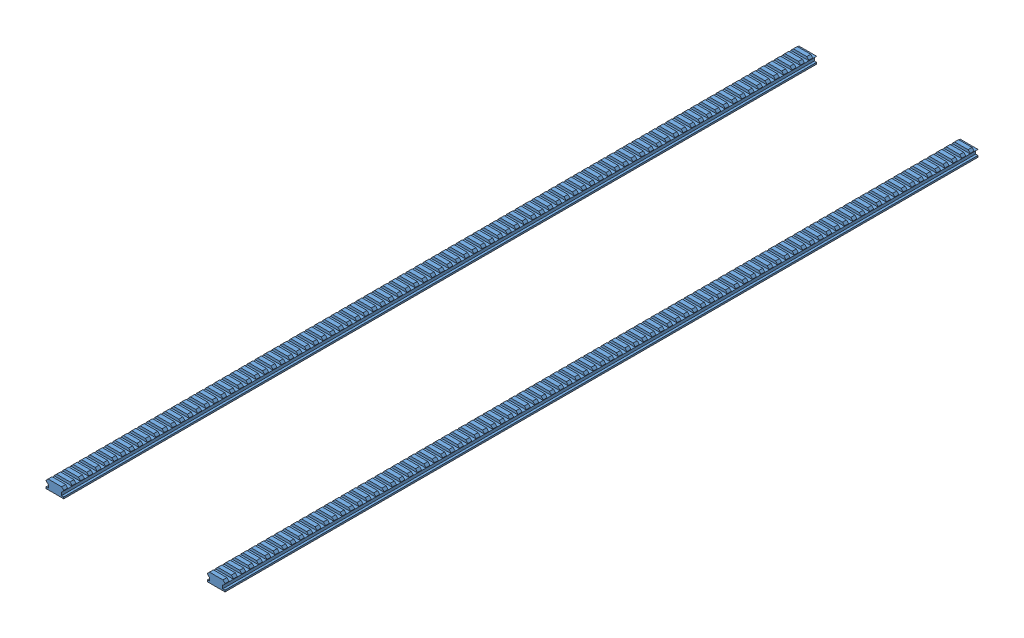
SolidWorks assembly SubASSEM_TopBottomRail, configuration Default. Lengths in mm.
Overall size (214.03 11.24 900).
2 component instances, 1 part files, 0 mates.
Components (placement in the parent):
- PART_PicRail-1: PART_PicRail [Default] at (-96.4103 108.7891 464.3935) size (21.21 11.24 900)
- PART_PicRail-2: PART_PicRail [Default] at (96.4103 108.7891 464.3935) size (21.21 11.24 900)
